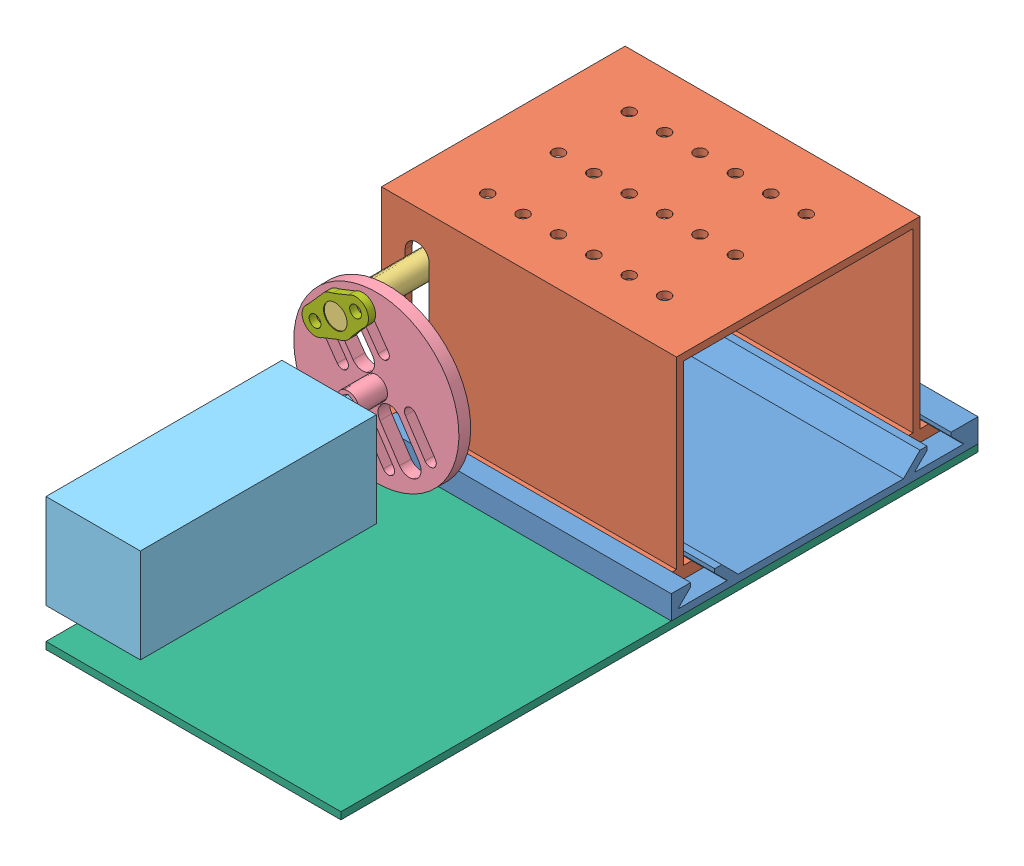
SolidWorks assembly assemblé, configuration Défaut. Lengths in mm.
Overall size (153.77 97.53 270).
7 component instances, 7 part files, 18 mates.
Components (placement in the parent):
- base-1: base [Défaut] at (-57.6507 4.3618 130) size (125 10 130)
- glissière-1: glissière [Défaut] at (-57.2396 22.4618 115.225) x (1 0 0) z (0 -1 0) size (125 120.25 83)
- tige filetée-1: tige filetée [Défaut] at (-52.0396 68.0059 12.6875) x (0.909403 0.415915 0) z (0.415915 -0.909403 0) size (10 140 10)
- oscillant-1: oscillant [Défaut] at (-37.6507 47.5618 145) x (0.817763 0.575555 0) z (0 0 1) size (70 70 17)
- moteur simpliste-1: moteur simpliste [Défaut] at (-17.6507 17.5618 170) x (-1 0 0) z (0 0 -1) size (40 40 120)
- planche support-1: planche support [Défaut] at (-57.6507 1.3618 270) size (125 3 270)
- vérou d'axe-1: vérou d'axe [Défaut] at (-52.0396 68.0059 153) x (0.817763 0.575555 0) z (-0.575555 0.817763 0) size (32 3 16)
Mates (geometry in assembly coordinates):
- Symétrique2: symmetric aligned: plane of base-1 through (-57.6507 4.3618 66.6) normal (0 0 -1); plane of glissière-1 through (-57.2396 22.4618 17.975) normal (0 0 1); plane of glissière-1 through (-57.2396 22.4618 115.225) normal (0 0 -1)
- Distance1: distance = 0.2 mm anti-aligned: plane of glissière-1 through (-57.2396 7.5618 118.225) normal (0 -1 0); plane of base-1 through (-79.4075 7.3618 127) normal (0 1 0)
- Tangent1: tangent anti-aligned: plane of glissière-1 through (-47.0396 22.4618 118.225) normal (-1 0 0); cylinder of tige filetée-1 through (-52.0396 68.0059 152.6875) axis (0 0 -1) radius 5
- Parallèle1: parallel anti-aligned: plane of glissière-1 through (-57.2396 22.4618 118.225) normal (0 0 1); plane of tige filetée-1 through (-52.0396 68.0059 12.6875) normal (0 0 -1)
- Tangent3: tangent anti-aligned: cylinder of tige filetée-1 through (-52.0396 68.0059 152.6875) axis (0 0 -1) radius 5; plane of oscillant-1 through (-33.5619 50.4396 150) normal (-0.817763 -0.575555 0)
- Coïncidente9: coincident aligned: line of oscillant-1 through (-37.6507 47.5618 150) axis (0 0 -1); line of moteur simpliste-1 through (-37.6507 47.5618 305.662) axis (0 0 -1)
- Coïncidente10: coincident anti-aligned: plane of oscillant-1 through (-37.6507 47.5618 150) normal (0 0 1); plane of moteur simpliste-1 through (-17.6507 17.5618 150) normal (0 0 -1)
- Coïncidente11: coincident anti-aligned: plane of base-1 through (-57.6507 4.3618 130) normal (0 -1 0); plane of planche support-1 through (-57.6507 4.3618 270) normal (0 1 0)
- Coïncidente12: coincident aligned: plane of base-1 through (-57.6507 14.3618 0) normal (0 0 -1); plane of planche support-1 through (-57.6507 4.3618 0) normal (0 0 -1)
- Coïncidente13: coincident aligned: plane of base-1 through (67.3493 14.3618 130) normal (1 0 0); plane of planche support-1 through (67.3493 4.3618 270) normal (1 0 0)
- Parallèle2: parallel anti-aligned: plane of moteur simpliste-1 through (-17.6507 17.5618 170) normal (0 -1 0); plane of planche support-1 through (-57.6507 4.3618 270) normal (0 1 0)
- Coïncidente16: coincident aligned: plane of moteur simpliste-1 through (-57.6507 57.5618 170) normal (-1 0 0); plane of planche support-1 through (-57.6507 4.3618 270) normal (-1 0 0)
- Coïncidente21: coincident: plane of glissière-1 through (-57.2396 47.5618 115.225) normal (0 -1 0); line of moteur simpliste-1 through (-37.6507 47.5618 305.662) axis (0 0 -1)
- Coïncidente22: coincident aligned: plane of moteur simpliste-1 through (-17.6507 57.5618 270) normal (0 0 1); plane of planche support-1 through (-57.6507 4.3618 270) normal (0 0 1)
- Distance2: distance = 0 mm: cylinder of oscillant-1 through (-52.0396 68.0059 150) axis (0 0 -1) radius 5; cylinder of tige filetée-1 through (-52.0396 68.0059 152.6875) axis (0 0 -1) radius 5
- Coaxiale2: concentric anti-aligned: cylinder of tige filetée-1 through (-52.0396 68.0059 152.6875) axis (0 0 -1) radius 5; cylinder of vérou d'axe-1 through (-52.0396 68.0059 150) axis (0 0 1) radius 5
- Coïncidente23: coincident anti-aligned: plane of oscillant-1 through (-37.6507 47.5618 150) normal (0 0 1); plane of vérou d'axe-1 through (-52.0396 68.0059 150) normal (0 0 -1)
- Parallèle5: parallel: plane of oscillant-1 through (-44.1928 42.9574 150) normal (-0.817763 -0.575555 0); line of vérou d'axe-1 through (-60.6261 61.9626 153) axis (0.575555 -0.817763 0)
